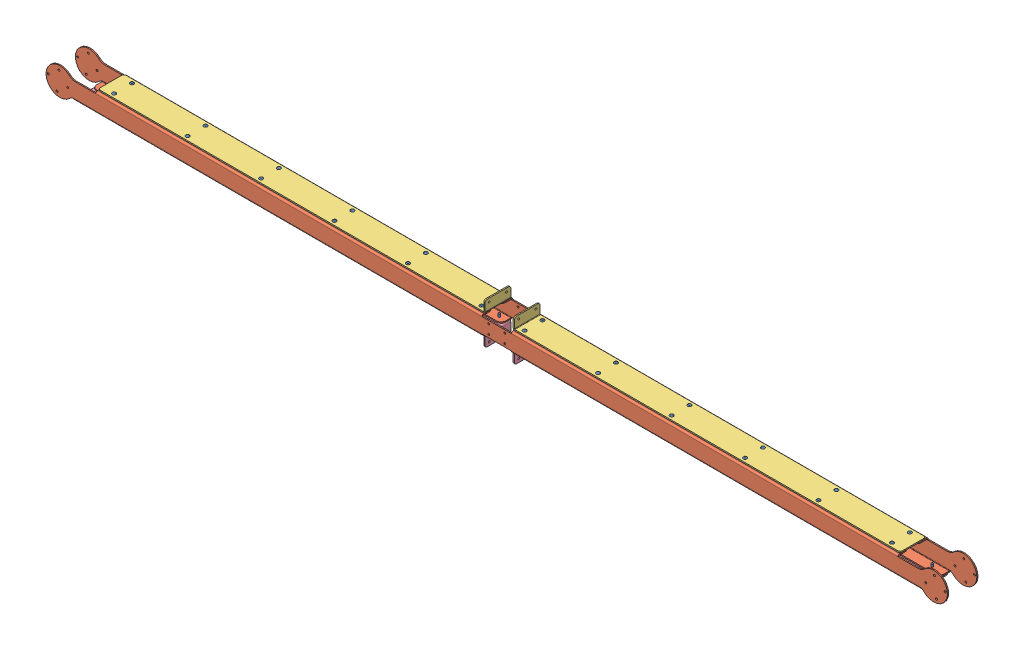
SolidWorks assembly GE-20010 - 28, configuration Default. Lengths in mm.
Overall size (2489.2 114.12 84.32).
54 component instances, 4 part files, 31 mates.
Components (placement in the parent):
- rivet_.1875_.251-.375-32: rivet_.1875_.251-.375 [Default] at (-59.6201 28.575 14.2875) x (0.428815 0 -0.903392) z (0 1 0) size (10.01 10.01 16.21)
- rivet_.1875_.251-.375-26: rivet_.1875_.251-.375 [Default] at (-59.6201 28.575 63.5) x (0.428815 0 -0.903392) z (0 1 0) size (10.01 10.01 16.21)
- rivet_.1875_.251-.375-4: rivet_.1875_.251-.375 [Default] at (59.6201 28.575 14.2875) x (0.428815 0 -0.903392) z (0 1 0) size (10.01 10.01 16.21)
- rivet_.1875_.251-.375-38: rivet_.1875_.251-.375 [Default] at (59.6201 28.575 63.5) x (0.428815 0 -0.903392) z (0 1 0) size (10.01 10.01 16.21)
- rivet_.1875_.251-.375-44: rivet_.1875_.251-.375 [Default] at (-59.6201 -28.575 14.2875) x (-0.625558 0 -0.780178) z (0 -1 0) size (10.01 10.01 16.21)
- rivet_.1875_.251-.375-126: rivet_.1875_.251-.375 [Default] at (-59.6201 -28.575 63.5) x (-0.625558 0 -0.780178) z (0 -1 0) size (10.01 10.01 16.21)
- rivet_.1875_.251-.375-50: rivet_.1875_.251-.375 [Default] at (59.6201 -28.575 63.5) x (-0.625558 0 -0.780178) z (0 -1 0) size (10.01 10.01 16.21)
- rivet_.1875_.251-.375-120: rivet_.1875_.251-.375 [Default] at (59.6201 -28.575 14.2875) x (-0.625558 0 -0.780178) z (0 -1 0) size (10.01 10.01 16.21)
- GE-20010 - 06-1: GE-20010 - 06 [Default] at origin size (2489.2 76.2 31.75)
- GE-20010 - 06-2: GE-20010 - 06 [Default] at (0 0 77.7875) x (-1 0 0) z (0 0 -1) size (2489.2 76.2 31.75)
- GE-20010 - 07-1: GE-20010 - 07 [Default] at (43.5166 28.575 38.8937) x (-1 0 0) z (0 0 -1) size (1068.46 31.75 71.44)
- GE-20010 - 08-1: GE-20010 - 08 [Default] at (-43.5166 -28.575 38.8937) x (1 0 0) z (0 0 -1) size (1131 31.75 71.44)
- GE-20010 - 07-2: GE-20010 - 07 [Default] at (-43.5166 28.575 38.8937) size (1068.46 31.75 71.44)
- GE-20010 - 08-2: GE-20010 - 08 [Default] at (43.5166 -28.575 38.8937) x (-1 0 0) z (0 0 1) size (1131 31.75 71.44)
- rivet_.1875_.251-.375-27: rivet_.1875_.251-.375 [Default] at (-262.5027 28.575 63.5) x (0.428815 0 -0.903392) z (0 1 0) size (10.01 10.01 16.21)
- rivet_.1875_.251-.375-28: rivet_.1875_.251-.375 [Default] at (-465.3852 28.575 63.5) x (0.428815 0 -0.903392) z (0 1 0) size (10.01 10.01 16.21)
- rivet_.1875_.251-.375-29: rivet_.1875_.251-.375 [Default] at (-668.2677 28.575 63.5) x (0.428815 0 -0.903392) z (0 1 0) size (10.01 10.01 16.21)
- rivet_.1875_.251-.375-30: rivet_.1875_.251-.375 [Default] at (-871.1501 28.575 63.5) x (0.428815 0 -0.903392) z (0 1 0) size (10.01 10.01 16.21)
- rivet_.1875_.251-.375-31: rivet_.1875_.251-.375 [Default] at (-1074.0326 28.575 63.5) x (0.428815 0 -0.903392) z (0 1 0) size (10.01 10.01 16.21)
- rivet_.1875_.251-.375-33: rivet_.1875_.251-.375 [Default] at (-262.5027 28.575 14.2875) x (0.428815 0 -0.903392) z (0 1 0) size (10.01 10.01 16.21)
- rivet_.1875_.251-.375-34: rivet_.1875_.251-.375 [Default] at (-465.3852 28.575 14.2875) x (0.428815 0 -0.903392) z (0 1 0) size (10.01 10.01 16.21)
- rivet_.1875_.251-.375-35: rivet_.1875_.251-.375 [Default] at (-668.2677 28.575 14.2875) x (0.428815 0 -0.903392) z (0 1 0) size (10.01 10.01 16.21)
- rivet_.1875_.251-.375-36: rivet_.1875_.251-.375 [Default] at (-871.1501 28.575 14.2875) x (0.428815 0 -0.903392) z (0 1 0) size (10.01 10.01 16.21)
- rivet_.1875_.251-.375-37: rivet_.1875_.251-.375 [Default] at (-1074.0326 28.575 14.2875) x (0.428815 0 -0.903392) z (0 1 0) size (10.01 10.01 16.21)
- rivet_.1875_.251-.375-39: rivet_.1875_.251-.375 [Default] at (262.5027 28.575 63.5) x (0.428815 0 -0.903392) z (0 1 0) size (10.01 10.01 16.21)
- rivet_.1875_.251-.375-40: rivet_.1875_.251-.375 [Default] at (465.3852 28.575 63.5) x (0.428815 0 -0.903392) z (0 1 0) size (10.01 10.01 16.21)
- rivet_.1875_.251-.375-41: rivet_.1875_.251-.375 [Default] at (668.2677 28.575 63.5) x (0.428815 0 -0.903392) z (0 1 0) size (10.01 10.01 16.21)
- rivet_.1875_.251-.375-42: rivet_.1875_.251-.375 [Default] at (871.1501 28.575 63.5) x (0.428815 0 -0.903392) z (0 1 0) size (10.01 10.01 16.21)
- rivet_.1875_.251-.375-43: rivet_.1875_.251-.375 [Default] at (1074.0326 28.575 63.5) x (0.428815 0 -0.903392) z (0 1 0) size (10.01 10.01 16.21)
- rivet_.1875_.251-.375-21: rivet_.1875_.251-.375 [Default] at (262.5027 28.575 14.2875) x (0.428815 0 -0.903392) z (0 1 0) size (10.01 10.01 16.21)
- rivet_.1875_.251-.375-22: rivet_.1875_.251-.375 [Default] at (465.3852 28.575 14.2875) x (0.428815 0 -0.903392) z (0 1 0) size (10.01 10.01 16.21)
- rivet_.1875_.251-.375-23: rivet_.1875_.251-.375 [Default] at (668.2677 28.575 14.2875) x (0.428815 0 -0.903392) z (0 1 0) size (10.01 10.01 16.21)
- rivet_.1875_.251-.375-24: rivet_.1875_.251-.375 [Default] at (871.1501 28.575 14.2875) x (0.428815 0 -0.903392) z (0 1 0) size (10.01 10.01 16.21)
- rivet_.1875_.251-.375-25: rivet_.1875_.251-.375 [Default] at (1074.0326 28.575 14.2875) x (0.428815 0 -0.903392) z (0 1 0) size (10.01 10.01 16.21)
- rivet_.1875_.251-.375-45: rivet_.1875_.251-.375 [Default] at (-274.8852 -28.575 14.2875) x (-0.625558 0 -0.780178) z (0 -1 0) size (10.01 10.01 16.21)
- rivet_.1875_.251-.375-46: rivet_.1875_.251-.375 [Default] at (-490.1501 -28.575 14.2875) x (-0.625558 0 -0.780178) z (0 -1 0) size (10.01 10.01 16.21)
- rivet_.1875_.251-.375-47: rivet_.1875_.251-.375 [Default] at (-705.4152 -28.575 14.2875) x (-0.625558 0 -0.780178) z (0 -1 0) size (10.01 10.01 16.21)
- rivet_.1875_.251-.375-48: rivet_.1875_.251-.375 [Default] at (-920.6802 -28.575 14.2875) x (-0.625558 0 -0.780178) z (0 -1 0) size (10.01 10.01 16.21)
- rivet_.1875_.251-.375-49: rivet_.1875_.251-.375 [Default] at (-1135.9452 -28.575 14.2875) x (-0.625558 0 -0.780178) z (0 -1 0) size (10.01 10.01 16.21)
- rivet_.1875_.251-.375-127: rivet_.1875_.251-.375 [Default] at (-274.8852 -28.575 63.5) x (-0.625558 0 -0.780178) z (0 -1 0) size (10.01 10.01 16.21)
- rivet_.1875_.251-.375-128: rivet_.1875_.251-.375 [Default] at (-490.1501 -28.575 63.5) x (-0.625558 0 -0.780178) z (0 -1 0) size (10.01 10.01 16.21)
- rivet_.1875_.251-.375-129: rivet_.1875_.251-.375 [Default] at (-705.4152 -28.575 63.5) x (-0.625558 0 -0.780178) z (0 -1 0) size (10.01 10.01 16.21)
- rivet_.1875_.251-.375-130: rivet_.1875_.251-.375 [Default] at (-920.6802 -28.575 63.5) x (-0.625558 0 -0.780178) z (0 -1 0) size (10.01 10.01 16.21)
- rivet_.1875_.251-.375-131: rivet_.1875_.251-.375 [Default] at (-1135.9452 -28.575 63.5) x (-0.625558 0 -0.780178) z (0 -1 0) size (10.01 10.01 16.21)
- rivet_.1875_.251-.375-121: rivet_.1875_.251-.375 [Default] at (274.8852 -28.575 14.2875) x (-0.625558 0 -0.780178) z (0 -1 0) size (10.01 10.01 16.21)
- rivet_.1875_.251-.375-122: rivet_.1875_.251-.375 [Default] at (490.1501 -28.575 14.2875) x (-0.625558 0 -0.780178) z (0 -1 0) size (10.01 10.01 16.21)
- rivet_.1875_.251-.375-123: rivet_.1875_.251-.375 [Default] at (705.4152 -28.575 14.2875) x (-0.625558 0 -0.780178) z (0 -1 0) size (10.01 10.01 16.21)
- rivet_.1875_.251-.375-124: rivet_.1875_.251-.375 [Default] at (920.6802 -28.575 14.2875) x (-0.625558 0 -0.780178) z (0 -1 0) size (10.01 10.01 16.21)
- rivet_.1875_.251-.375-125: rivet_.1875_.251-.375 [Default] at (1135.9452 -28.575 14.2875) x (-0.625558 0 -0.780178) z (0 -1 0) size (10.01 10.01 16.21)
- rivet_.1875_.251-.375-115: rivet_.1875_.251-.375 [Default] at (274.8852 -28.575 63.5) x (-0.625558 0 -0.780178) z (0 -1 0) size (10.01 10.01 16.21)
- rivet_.1875_.251-.375-116: rivet_.1875_.251-.375 [Default] at (490.1501 -28.575 63.5) x (-0.625558 0 -0.780178) z (0 -1 0) size (10.01 10.01 16.21)
- rivet_.1875_.251-.375-117: rivet_.1875_.251-.375 [Default] at (705.4152 -28.575 63.5) x (-0.625558 0 -0.780178) z (0 -1 0) size (10.01 10.01 16.21)
- rivet_.1875_.251-.375-118: rivet_.1875_.251-.375 [Default] at (920.6802 -28.575 63.5) x (-0.625558 0 -0.780178) z (0 -1 0) size (10.01 10.01 16.21)
- rivet_.1875_.251-.375-119: rivet_.1875_.251-.375 [Default] at (1135.9452 -28.575 63.5) x (-0.625558 0 -0.780178) z (0 -1 0) size (10.01 10.01 16.21)
Mates (geometry in assembly coordinates):
- Coincident1: coincident anti-aligned: plane of GE-20010 - 06-1 through (0 25.3111 0) normal (0 1 0); plane of GE-20010 - 07-1 through (43.5166 25.3111 38.8937) normal (0 -1 0)
- Coincident2: coincident anti-aligned: plane of GE-20010 - 06-1 through (0 25.3111 0) normal (0 1 0); plane of GE-20010 - 07-2 through (-43.5166 25.3111 38.8937) normal (0 -1 0)
- Coincident3: coincident anti-aligned: plane of GE-20010 - 06-1 through (0 -25.3111 0) normal (0 -1 0); plane of GE-20010 - 08-2 through (43.5166 -25.3111 38.8937) normal (0 1 0)
- Coincident4: coincident anti-aligned: plane of GE-20010 - 06-1 through (0 -25.3111 0) normal (0 -1 0); plane of GE-20010 - 08-1 through (-43.5166 -25.3111 38.8937) normal (0 1 0)
- Concentric1: concentric aligned: cylinder of GE-20010 - 06-1 through (59.6201 25.3111 14.2875) axis (0 1 0) radius 2.4574; cylinder of GE-20010 - 07-1 through (59.6201 28.575 14.2875) axis (0 1 0) radius 2.4574
- Concentric2: concentric aligned: cylinder of GE-20010 - 06-1 through (-59.6201 25.3111 14.2875) axis (0 1 0) radius 2.4574; cylinder of GE-20010 - 07-2 through (-59.6201 28.575 14.2875) axis (0 1 0) radius 2.4574
- Concentric3: concentric aligned: cylinder of GE-20010 - 06-1 through (-59.6201 -25.3111 14.2875) axis (0 -1 0) radius 2.4574; cylinder of GE-20010 - 08-1 through (-59.6201 -28.575 14.2875) axis (0 -1 0) radius 2.4574
- Concentric4: concentric aligned: cylinder of GE-20010 - 06-1 through (-1135.9452 -25.3111 14.2875) axis (0 -1 0) radius 2.4574; cylinder of GE-20010 - 08-1 through (-1135.9452 -28.575 14.2875) axis (0 -1 0) radius 2.4574
- Concentric5: concentric aligned: cylinder of GE-20010 - 06-1 through (-1074.0326 25.3111 14.2875) axis (0 1 0) radius 2.4574; cylinder of GE-20010 - 07-2 through (-1074.0326 28.575 14.2875) axis (0 1 0) radius 2.4574
- Concentric6: concentric aligned: cylinder of GE-20010 - 06-1 through (1074.0326 25.3111 14.2875) axis (0 1 0) radius 2.4574; cylinder of GE-20010 - 07-1 through (1074.0326 28.575 14.2875) axis (0 1 0) radius 2.4574
- Concentric7: concentric aligned: cylinder of GE-20010 - 06-1 through (1135.9452 -25.3111 14.2875) axis (0 -1 0) radius 2.4574; cylinder of GE-20010 - 08-2 through (1135.9452 -28.575 14.2875) axis (0 -1 0) radius 2.4574
- Concentric8: concentric aligned: cylinder of GE-20010 - 06-1 through (59.6201 -25.3111 14.2875) axis (0 -1 0) radius 2.4574; cylinder of GE-20010 - 08-2 through (59.6201 -28.575 14.2875) axis (0 -1 0) radius 2.4574
- Coincident5: coincident anti-aligned: plane of GE-20010 - 06-2 through (0 -25.3111 77.7875) normal (0 -1 0); plane of GE-20010 - 08-2 through (43.5166 -25.3111 38.8937) normal (0 1 0)
- Concentric9: concentric aligned: cylinder of GE-20010 - 06-2 through (59.6201 25.3111 63.5) axis (0 1 0) radius 2.4574; cylinder of GE-20010 - 07-1 through (59.6201 28.575 63.5) axis (0 1 0) radius 2.4574
- Concentric10: concentric aligned: cylinder of GE-20010 - 06-2 through (-59.6201 25.3111 63.5) axis (0 1 0) radius 2.4574; cylinder of GE-20010 - 07-2 through (-59.6201 28.575 63.5) axis (0 1 0) radius 2.4574
- Concentric11: concentric aligned: cylinder of GE-20010 - 07-2 through (-59.6201 28.575 63.5) axis (0 1 0) radius 2.4574; cylinder of rivet_.1875_.251-.375-26 through (-59.6201 13.97 63.5) axis (0 1 0) radius 2.3813
- Concentric12: concentric aligned: cylinder of GE-20010 - 07-2 through (-59.6201 28.575 14.2875) axis (0 1 0) radius 2.4574; cylinder of rivet_.1875_.251-.375-32 through (-59.6201 13.97 14.2875) axis (0 1 0) radius 2.3813
- Concentric13: concentric aligned: cylinder of GE-20010 - 07-1 through (59.6201 28.575 14.2875) axis (0 1 0) radius 2.4574; cylinder of rivet_.1875_.251-.375-4 through (59.6201 13.97 14.2875) axis (0 1 0) radius 2.3813
- Concentric14: concentric aligned: cylinder of GE-20010 - 07-1 through (59.6201 28.575 63.5) axis (0 1 0) radius 2.4574; cylinder of rivet_.1875_.251-.375-38 through (59.6201 13.97 63.5) axis (0 1 0) radius 2.3813
- Coincident6: coincident aligned: plane of GE-20010 - 07-1 through (43.5166 28.575 38.8937) normal (0 1 0); circle of rivet_.1875_.126-.25-5
- Coincident7: coincident aligned: plane of GE-20010 - 07-1 through (43.5166 28.575 38.8937) normal (0 1 0); circle of rivet_.1875_.126-.25-4
- Coincident8: coincident aligned: plane of GE-20010 - 07-2 through (-43.5166 28.575 38.8937) normal (0 1 0); circle of rivet_.1875_.126-.25-2
- Coincident9: coincident aligned: plane of GE-20010 - 07-2 through (-43.5166 28.575 38.8937) normal (0 1 0); circle of rivet_.1875_.126-.25-3
- Concentric15: concentric aligned: cylinder of GE-20010 - 08-1 through (-59.6201 -28.575 63.5) axis (0 -1 0) radius 2.4574; cylinder of rivet_.1875_.251-.375-126 through (-59.6201 -13.97 63.5) axis (0 -1 0) radius 2.3813
- Concentric16: concentric aligned: cylinder of GE-20010 - 08-1 through (-59.6201 -28.575 14.2875) axis (0 -1 0) radius 2.4574; cylinder of rivet_.1875_.251-.375-44 through (-59.6201 -13.97 14.2875) axis (0 -1 0) radius 2.3813
- Concentric17: concentric aligned: cylinder of GE-20010 - 08-2 through (59.6201 -28.575 14.2875) axis (0 -1 0) radius 2.4574; cylinder of rivet_.1875_.251-.375-120 through (59.6201 -13.97 14.2875) axis (0 -1 0) radius 2.3813
- Concentric18: concentric aligned: cylinder of GE-20010 - 08-2 through (59.6201 -28.575 63.5) axis (0 -1 0) radius 2.4574; cylinder of rivet_.1875_.251-.375-50 through (59.6201 -13.97 63.5) axis (0 -1 0) radius 2.3813
- Coincident10: coincident aligned: plane of GE-20010 - 08-1 through (-43.5166 -28.575 38.8937) normal (0 -1 0); circle of rivet_.1875_.126-.25-27
- Coincident11: coincident aligned: plane of GE-20010 - 08-1 through (-43.5166 -28.575 38.8937) normal (0 -1 0); circle of rivet_.1875_.126-.25-26
- Coincident12: coincident aligned: plane of GE-20010 - 08-2 through (43.5166 -28.575 38.8937) normal (0 -1 0); circle of rivet_.1875_.126-.25-28
- Coincident13: coincident aligned: plane of GE-20010 - 08-2 through (43.5166 -28.575 38.8937) normal (0 -1 0); circle of rivet_.1875_.126-.25-29
